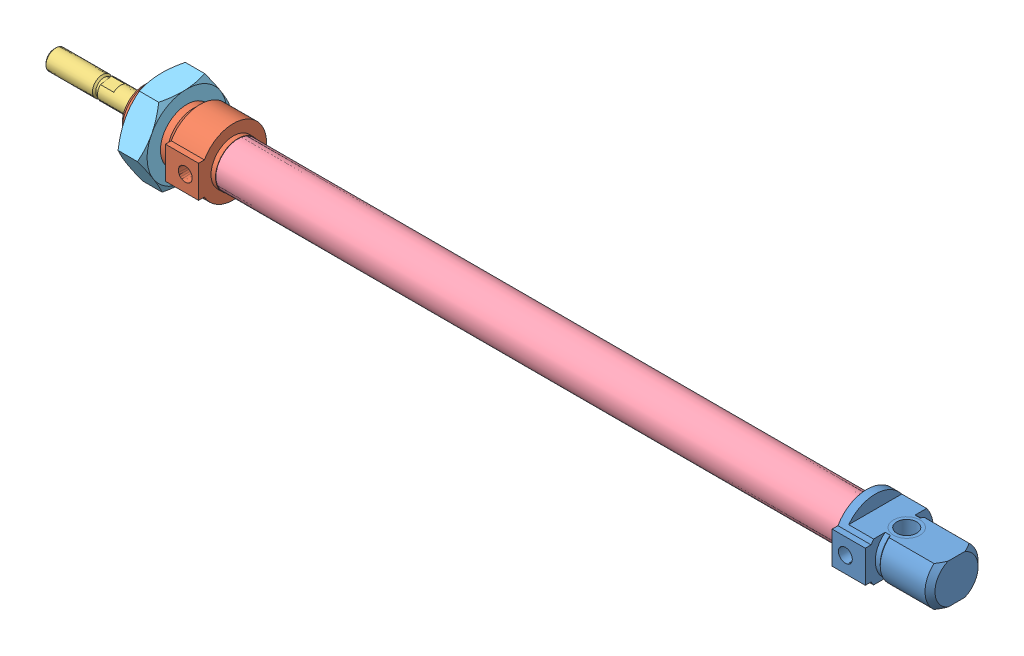
SolidWorks assembly Janatics-A51, A52 Series, configuration A51, A52 Series. Lengths in mm.
Overall size (272 36.26 35.11).
5 component instances, 5 part files, 16 mates.
Components (placement in the parent):
- Janatics-A51, A52 Series_REC-1(new)-1: Janatics-A51, A52 Series_REC-1(new) [DIA 12] x (-1 0 0) z (0 1 0) size (33 20.5 20)
- Janatics-A51, A52 Series_FEC(new)-1: Janatics-A51, A52 Series_FEC(new) [Default] at (-245 0 0) x (1 0 0) z (0 -1 0) size (33 20.5 20)
- Janatics-A51, A52 Series_piston rod (10C)(new)-1: Janatics-A51, A52 Series_piston rod (10C)(new) [DIA 12] at (-39 0 0) x (-1 0 0) z (0 0.984908 0.173078) size (233 12 12)
- Janatics-A51, A52 Series_cylinder barral (10A)(new)-1: Janatics-A51, A52 Series_cylinder barral (10A)(new) [Dia 12] at (554.2482 -0.0004 -0.0002) x (1 0 0) z (0 0.366126 -0.930565) size (188.3 13.3 13.3)
- Janatics-A51, A52 Series_lock nut Dia12-1: Janatics-A51, A52 Series_lock nut Dia12 [Dia 12] at (-240 0 0) x (1 0 0) z (0 0.84439 0.535729) size (8 24 27.71)
Mates (geometry in assembly coordinates):
- Concentric1: concentric aligned: cylinder of Janatics-A51, A52 Series_REC-1(new)-1 through (-45.5 0 0) axis (-1 0 0) radius 6
- Coincident2: coincident aligned: plane of Janatics-A51, A52 Series_REC-1(new)-1 through (0 0 0) normal (1 0 0)
- Concentric2: concentric aligned: cylinder of Janatics-A51, A52 Series_cylinder barral (10A)(new)-1 through (-212 0 0) axis (-1 0 0) radius 6
- Concentric3: concentric anti-aligned: cylinder of Janatics-A51, A52 Series_piston rod (10C)(new)-1 through (-12.6088 0 0) axis (1 0 0) radius 6
- Coincident9: coincident aligned: plane of Janatics-A51, A52 Series_FEC(new)-1 through (-212 0 0) normal (1 0 0)
- Concentric4: concentric anti-aligned: cylinder of Janatics-A51, A52 Series_FEC(new)-1 through (-199.5 0 0) axis (1 0 0) radius 6
- Coincident12: coincident anti-aligned: plane of Janatics-A51, A52 Series_REC-1(new)-1 through (-28.35 0 6.75) normal (-1 0 0); plane of Janatics-A51, A52 Series_cylinder barral (10A)(new)-1 through (-28.35 5.5834 2.1968) normal (1 0 0)
- Concentric5: concentric anti-aligned: cylinder of Janatics-A51, A52 Series_REC-1(new)-1 through (0 0 0) axis (1 0 0) radius 8; cylinder of Janatics-A51, A52 Series_lock nut Dia12-1 through (-240 0 0) axis (-1 0 0) radius 7.25
- Distance2: distance = 5 mm aligned: plane of Janatics-A51, A52 Series_FEC(new)-1 through (-245 0 0) normal (-1 0 0); plane of Janatics-A51, A52 Series_lock nut Dia12-1 through (-240 -11.7002 -7.4233) normal (-1 0 0)
- Concentric7: concentric anti-aligned: cylinder of Janatics-A51, A52 Series_piston rod (10C)(new)-1 through (-12.6088 0 0) axis (1 0 0) radius 3; cylinder of Janatics-A51, A52 Series_piston rod lock nut-1 through (-269 0 0) axis (-1 0 0) radius 2.5
- Distance3: distance = 3 mm aligned: plane of Janatics-A51, A52 Series_piston rod lock nut-1 through (-269 -0.2411 5.7685) normal (-1 0 0); plane of Janatics-A51, A52 Series_piston rod (10C)(new)-1 through (-272 0.5192 -2.9547) normal (-1 0 0)
- Coincident15: coincident aligned: plane of Janatics-A51, A52 Series_REC-1(new)-1 through (0 0 0) normal (0 0 1); plane of Janatics-A51, A52 Series_FEC(new)-1 through (-245 0 0) normal (0 0 1)
- Parallel3: parallel anti-aligned: plane of Janatics-A51, A52 Series_REC-1(new)-1 through (0 -6 8) normal (0 -1 0)
- Parallel9: parallel aligned: plane of Janatics-A51, A52 Series_lock nut Dia12-1 through (-232 -11.7002 -7.4233) normal (0 -0.463399 -0.88615); plane of Janatics-A51, A52 Series_piston rod lock nut-1 through (-266 -4.8751 -3.093) normal (0 -0.463399 -0.88615)
- Parallel10: parallel aligned: plane of Janatics-A51, A52 Series_piston rod (10C)(new)-1 through (-272 0.5192 -2.9547) normal (-1 0 0); plane of Janatics-A51, A52 Series_lock nut Dia12-1 through (-240 -11.7002 -7.4233) normal (-1 0 0)
- LimitDistance1: limit distance = 160 mm anti-aligned: plane of Janatics-A51, A52 Series_piston rod (10C)(new)-1 through (-58 0.5192 -2.9547) normal (-1 0 0); plane of Janatics-A51, A52 Series_FEC(new)-1 through (-218 0 14) normal (1 0 0)
